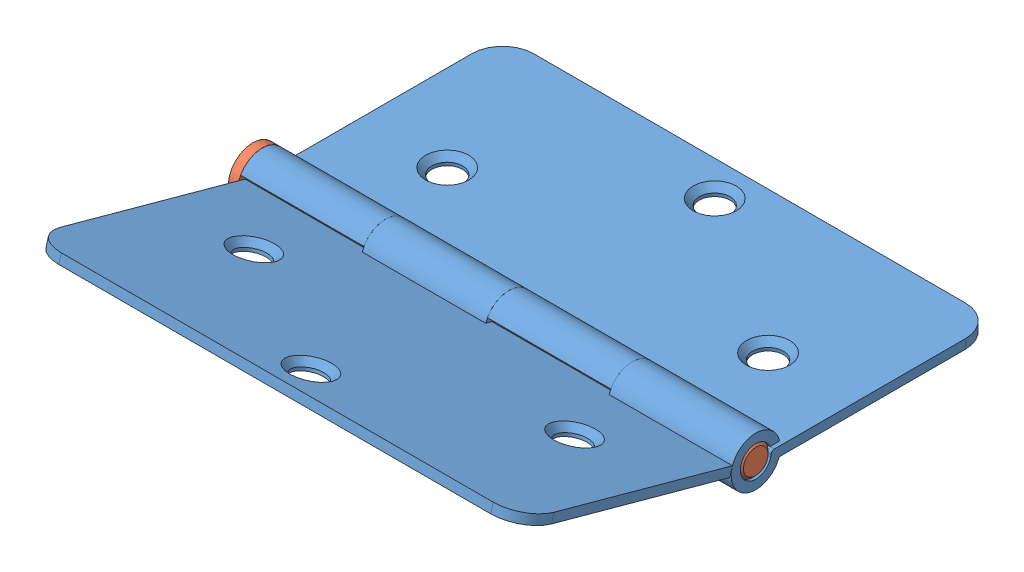
SolidWorks assembly Assem1, configuration Default. Lengths in mm.
Overall size (81.5 19.09 77.66).
3 component instances, 2 part files, 4 mates.
Components (placement in the parent):
- Part1-1: Part1 [Default] at (36.4477 47.6774 53.9034) size (80 8 42.99)
- Pin-1: Pin [Default] at (-5.0523 48.9388 75.3963) x (0 0 -1) z (1 0 0) size (8 8 81.5)
- Part1-2: Part1 [Default] at (36.4477 53.4072 96.4574) x (-1 0 0) z (0 -0.264501 -0.964385) size (80 8 42.99)
Mates (geometry in assembly coordinates):
- Hinge1: hinge anti-aligned: cylinder of Part1-2 through (16.4477 48.9388 75.3963) axis (-1 0 0) radius 2.5; cylinder of Part1-2 through (16.4477 48.9388 75.3963) axis (1 0 0) radius 2.5; plane of Part1-1 through (16.4477 47.4774 79.3339) normal (1 0 0); plane of Part1-1 through (16.4477 47.4774 71.4588) normal (-1 0 0)
- Concentric1: concentric anti-aligned: cylinder of Part1-1 through (56.4477 48.9388 75.3963) axis (1 0 0) radius 2.5; cylinder of pin-1 through (76.4477 48.9388 75.3963) axis (-1 0 0) radius 2.5
- Coincident1: coincident anti-aligned: plane of pin-1 through (-3.5523 48.9388 75.3963) normal (1 0 0); plane of Part1-2 through (-3.5523 49.1774 79.3892) normal (-1 0 0)
- LimitAngle2: limit planar angle = 2.873906 rad anti-aligned: plane of Part1-2 through (71.4477 58.1601 108.1155) normal (0 0.964385 -0.264501); plane of Part1-1 through (1.4477 49.1774 41.4034) normal (0 1 0)
